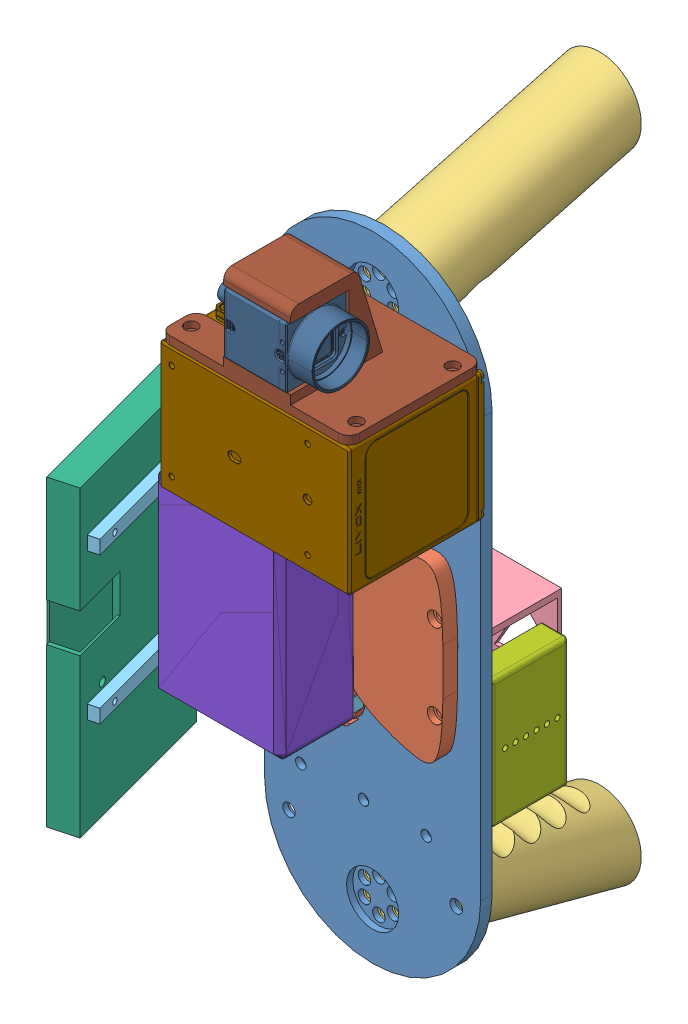
SolidWorks assembly r3live_handheld, configuration 默认. Lengths in mm.
Overall size (160.03 343.59 190.09).
16 component instances, 12 part files, 36 mates.
Components (placement in the parent):
- handheld_base-1: handheld_base [默认] at (-108.085 6.6665 297.8472) size (103.35 303.35 5.5)
- manifold_base-1: manifold_base [默认] at (-99.685 2.9754 303.3472) x (0 1 0) z (0 0 -1) size (107.54 146.93 7)
- handheld_handle-1: handheld_handle [默认] at (-72.3586 -114.8246 297.8472) x (0 1 0) z (1 0 0) size (66.79 103 45.47)
- handheld_handle-2: handheld_handle [默认] at (-72.3586 135.1754 297.8472) x (0 -1 0) z (-1 0 0) size (66.79 103 45.47)
- p4_battery-1: p4_battery [默认] at (-77.421 -32.8246 253.3472) x (0 -1 0) z (0 0 -1) size (92 90.11 51.5)
- screen_support_part_2-1: screen_support_part_2 [默认] at (-140.3114 -32.2746 339.6716) x (0 -1 0) z (-0.965926 0 0.258819) size (6.5 73.75 77.27)
- screen_support_part_2-2: screen_support_part_2 [默认] at (-140.3114 37.7254 339.6716) x (0 -1 0) z (-0.965926 0 0.258819) size (6.5 73.75 77.27)
- screen_support_part_1-1: screen_support_part_1 [默认] at (-144.6558 2.7254 342.7768) x (0 1 0) z (0.965926 0 -0.258819) size (145 78.65 14)
- batter_connection_board-1: batter_connection_board [默认] at (-25.421 -33.0696 279.0972) x (0 -1 0) z (-1 0 0) size (61.5 37.5 12.5)
- DJI_manifold2-1: DJI_manifold2 [Default] at (-135.685 51.4754 310.3472) x (0 1 0) z (1 0 0) size (91.01 35.01 61.01)
- AVIA-1: AVIA [Default] at (1.115 138.4754 287.4472) x (-1 0 0) z (0 1 0) size (91.02 64.8 76.07)
  - Livox_Avia_shell_FOV.stp-1: Livox_Avia_shell_FOV.stp [Default] at origin size (1207.64 1420.81 1420.81)
    - LIVOX_AVIA.stp-1: LIVOX_AVIA.stp [Default] at origin size (91.02 64.8 76.07)
    - LIVOX_AVIA_FOV.stp-1: LIVOX_AVIA_FOV.stp [Default] at (19.97 48.3 -38.5) x (0 0 -1) z (1 0 0) size (1420.81 1420.81 1123.13) (hidden)
- FL2-020-R0-1: FL2-020-R0 [Default] at (-61.0668 153.5754 354.2472) x (0 1 0) z (1 0 0) size (29 29 47.76)
- LiDAR_Camer_connector-1: LiDAR_Camer_connector [默认] at (-64.185 130.5754 335.7472) x (-1 0 0) z (0 1 0) size (90 64 44)
Mates (geometry in assembly coordinates):
- Coincident2: coincident anti-aligned: plane of all_parts_holder-1 through (-108.085 6.6665 297.8472) normal (0 0 -1); plane of hand_hold_part-1 through (-72.3586 -114.8246 297.8472) normal (0 0 1)
- Concentric1: concentric anti-aligned: circle of all_parts_holder-1; circle of hand_hold_part-1
- Concentric2: concentric anti-aligned: cylinder of all_parts_holder-1; cylinder of hand_hold_part-1 through (-72.3586 -122.8246 287.8472) axis (0 0 1) radius 1.9
- Coincident3: coincident anti-aligned: plane of all_parts_holder-1 through (-108.085 6.6665 297.8472) normal (0 0 -1); plane of hand_hold_part-2 through (-72.3586 135.1754 297.8472) normal (0 0 1)
- Concentric3: concentric aligned: circle of all_parts_holder-1; cylinder of hand_hold_part-2 through (-72.3586 127.1754 287.8472) axis (0 0 1) radius 1.9
- Concentric4: concentric aligned: circle of all_parts_holder-1; cylinder of hand_hold_part-2 through (-72.3586 143.1754 287.8472) axis (0 0 1) radius 1.9
- 同心1: concentric aligned: circle of all_parts_holder-1; circle of p4_battery-1
- 重合1: coincident anti-aligned: circle of all_parts_holder-1; cylinder of p4_battery-1 through (-46.7216 10.1754 294.8472) axis (0 0 1) radius 1.5
- 重合2: coincident anti-aligned: plane of all_parts_holder-1 through (-108.085 6.6665 297.8472) normal (0 0 -1); plane of p4_battery-1 through (-77.421 -32.8246 297.8472) normal (0 0 1)
- Coincident5: coincident anti-aligned: plane of all_parts_holder-1 through (-108.085 6.6665 303.3472) normal (0 0 1); plane of mid100_tx2_holder_2-1 through (-99.685 2.9754 303.3472) normal (0 0 -1)
- Coincident6: coincident aligned: plane of display_holder_part_2-1 through (-145.1411 -32.2746 340.9657) normal (-0.965926 0 0.258819); plane of display_holder_part_2-2 through (-145.1411 37.7254 340.9657) normal (-0.965926 0 0.258819)
- Coincident13: coincident anti-aligned: plane of mid100_tx2_holder_2-1 through (-99.685 2.9754 305.3472) normal (0 0 1); plane of display_holder_part_2-2 through (-140.3114 117.192 305.3472) normal (0 0 -1)
- Coincident14: coincident anti-aligned: plane of mid100_tx2_holder_2-1 through (-99.685 34.4754 310.3472) normal (0 1 0); plane of display_holder_part_2-2 through (-135.5971 34.4754 376.5842) normal (0 -1 0)
- Parallel3: parallel anti-aligned: plane of all_parts_holder-1 through (-20.685 -89.8246 303.3472) normal (1 0 0); plane of mid100_tx2_holder_2-1 through (-141.685 2.9754 310.3472) normal (-1 0 0)
- Coincident16: coincident aligned: plane of mid100_tx2_holder_2-1 through (-74.685 2.9754 310.3472) normal (1 0 0); plane of display_holder_part_2-2 through (-74.685 117.192 339.6716) normal (1 0 0)
- Coincident18: coincident anti-aligned: plane of display_holder_part_2-1 through (-145.1411 -32.2746 340.9657) normal (-0.965926 0 0.258819); plane of screen_support_part_1-1 through (-144.6558 2.7254 342.7768) normal (0.965926 0 -0.258819)
- Concentric6: concentric anti-aligned: circle of display_holder_part_2-1; cylinder of screen_support_part_1-1 through (-154.024 -32.2746 319.4051) axis (0.965926 0 -0.258819) radius 1.4
- Concentric7: concentric anti-aligned: circle of display_holder_part_2-1; circle of display_holder_with_screen-1
- Concentric8: concentric aligned: circle of display_holder_part_2-2; circle of display_holder_with_screen-1
- Concentric9: concentric anti-aligned: circle of display_holder_part_2-2; circle of display_holder_with_screen-1
- Coincident23: coincident anti-aligned: plane of all_parts_holder-1 through (-108.085 6.6665 297.8472) normal (0 0 -1); plane of batter_ee_board-1 through (-21.421 -33.0696 297.8472) normal (0 0 1)
- Coincident24: coincident anti-aligned: plane of p4_battery-1 through (-33.921 -32.8246 251.3472) normal (1 0 0); plane of batter_ee_board-1 through (-33.921 -33.0696 279.0972) normal (-1 0 0)
- Tangent1: tangent: plane of mid100_tx2_holder_2-1 through (-99.685 4.7254 307.8472) normal (0 -1 0); circle of DJI_manifold2-1
- Tangent2: tangent: plane of mid100_tx2_holder_2-1 through (-99.685 4.7254 307.8472) normal (0 -1 0); circle of DJI_manifold2-1
- Coincident27: coincident anti-aligned: plane of mid100_tx2_holder_2-1 through (-99.685 2.9754 310.3472) normal (0 0 1); plane of DJI_manifold2-1 through (-135.685 51.4754 310.3472) normal (0 0 -1)
- Coincident28: coincident aligned: plane of display_holder_part_2-2 through (-74.685 117.192 339.6716) normal (1 0 0); plane of DJI_manifold2-1 through (-74.685 51.4754 345.3472) normal (1 0 0)
- Concentric10: concentric aligned: cylinder of AVIA-1/Livox_Avia_shell_FOV.stp-1/LIVOX_AVIA.stp-1 through (-103.685 125.9874 312.7472) axis (0 1 0) radius 1.25; circle of Case_L_v3-1
- Concentric11: concentric aligned: cylinder of AVIA-1/Livox_Avia_shell_FOV.stp-1/LIVOX_AVIA.stp-1 through (-24.685 125.9874 358.7472) axis (0 1 0) radius 1.25; circle of Case_L_v3-1
- Coincident29: coincident anti-aligned: plane of AVIA-1/Livox_Avia_shell_FOV.stp-1/LIVOX_AVIA.stp-1 through (-64.185 130.5754 337.0972) normal (0 1 0); plane of Case_L_v3-1 through (-105.185 130.5754 363.7472) normal (0 -1 0)
- Coincident30: coincident anti-aligned: plane of FL2-020-R0-1 through (-51.685 140.0754 339.7472) normal (0 0 -1); plane of Case_L_v3-1 through (-64.185 130.5754 339.7472) normal (0 0 1)
- Concentric12: concentric aligned: cylinder of FL2-020-R0-1 through (-74.885 153.5754 339.7472) axis (0 0 -1) radius 1.5; cylinder of Case_L_v3-1 through (-74.885 153.5754 338.7472) axis (0 0 -1) radius 3
- Parallel4: parallel aligned: plane of FL2-020-R0-1 through (-51.685 168.0754 340.7472) normal (0 1 0); plane of Case_L_v3-1 through (-47.185 138.8254 339.7472) normal (0 1 0)
- Parallel5: parallel aligned: plane of all_parts_holder-1 through (-20.685 -89.8246 303.3472) normal (1 0 0); plane of AVIA-1/Livox_Avia_shell_FOV.stp-1/LIVOX_AVIA.stp-1 through (-18.685 99.9754 337.0972) normal (1 0 0)
- Coincident33: coincident anti-aligned: plane of all_parts_holder-1 through (-108.085 6.6665 303.3472) normal (0 0 1); plane of AVIA-1/Livox_Avia_shell_FOV.stp-1/LIVOX_AVIA.stp-1 through (-64.185 99.9754 303.3472) normal (0 0 -1)
- Concentric15: concentric aligned: circle of all_parts_holder-1; circle of mid100_tx2_holder_2-1
- Concentric16: concentric anti-aligned: cylinder of all_parts_holder-1 through (-38.685 76.9754 300.3472) axis (0 0 1) radius 3; cylinder of AVIA-1/Livox_Avia_shell_FOV.stp-1/LIVOX_AVIA.stp-1 through (-38.685 76.9754 307.9352) axis (0 0 -1) radius 1.25
